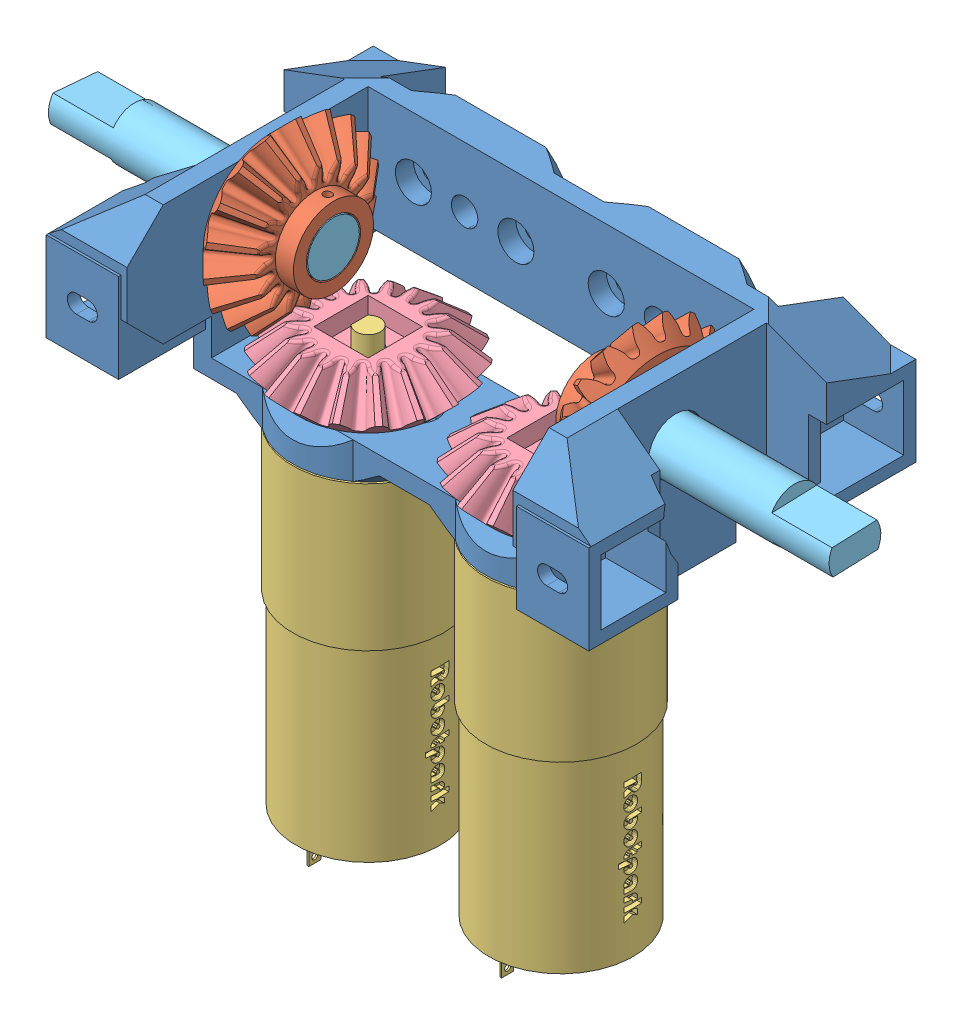
SolidWorks assembly Gearbox, configuration Default. Lengths in mm.
Overall size (157.67 110.2 59.04).
11 component instances, 5 part files, 21 mates.
Components (placement in the parent):
- Gearholder fine-1: Gearholder fine [Default] at (21.198 24.8446 19.4226) size (90 38 54.25)
- Bevel_Gear_18M3-2: Bevel_Gear_18M3 [Bevel01] at (39.7086 24.8446 38.4226) x (0 0.996387 -0.084925) z (1 0 0) size (54 54 28.01)
- Bevel_Gear_18M3-4: Bevel_Gear_18M3 [Bevel01] at (47.6874 24.8446 38.4226) x (0 -0.999352 -0.036007) z (-1 0 0) size (54 54 28.01)
- 25mm motor-1: 25mm motor [Default] at (47.7521 50.945 40.6836) x (0 -1 0) z (1 0 0) size (72.75 25 25)
  - A$C0AAA4746-1: A$C0AAA4746 [Default] at (70.7254 2.2611 11.9459) size (72.75 25 25)
- 25mm motor-2: 25mm motor [Default] at (15.7521 50.945 40.6836) x (0 -1 0) z (1 0 0) size (72.75 25 25)
  - A$C0AAA4746-1: A$C0AAA4746 [Default] at (70.7254 2.2611 11.9459) size (72.75 25 25)
- Bevel Gear Motor-1: Bevel Gear Motor [Bevel01] at (27.698 37.1053 38.4226) x (-1 0 0) z (0 1 0) size (54 54 28.01)
- Bevel Gear Motor-2: Bevel Gear Motor [Bevel01] at (59.698 37.1053 38.4226) x (-1 0 0) z (0 1 0) size (54 54 28.01)
- shaft - V2-1: shaft - V2 [Default] at (21.944 24.8446 38.4226) x (0 0.084925 0.996387) z (0 -0.996387 0.084925) size (9 57.08 9)
- shaft - V2-2: shaft - V2 [Default] at (65.452 24.8446 38.4226) x (0 0.036007 -0.999352) z (0 -0.999352 -0.036007) size (9 57.08 9)
Mates (geometry in assembly coordinates):
- Coincident2: coincident anti-aligned: plane of Gearholder fine-1 through (11.698 34.8446 62.4226) normal (1 0 0); plane of Bevel_Gear_18M3-2 through (11.698 24.8446 38.4226) normal (-1 0 0)
- Concentric2: concentric aligned: cylinder of Gearholder fine-1 through (78.698 24.8446 38.4226) axis (-1 0 0) radius 4.55; cylinder of Bevel_Gear_18M3-2 through (18.995 24.8446 38.4226) axis (-1 0 0) radius 4.5
- Concentric4: concentric anti-aligned: cylinder of Gearholder fine-1 through (78.698 24.8446 38.4226) axis (-1 0 0) radius 4.55; cylinder of Bevel_Gear_18M3-4 through (68.401 24.8446 38.4226) axis (1 0 0) radius 4.5
- Coincident4: coincident anti-aligned: plane of Gearholder fine-1 through (75.698 34.8446 82.6463) normal (-1 0 0); plane of Bevel_Gear_18M3-4 through (75.698 24.8446 38.4226) normal (1 0 0)
- Concentric11: concentric anti-aligned: cylinder of Bevel_Gear_18M3-2 through (18.995 24.8446 38.4226) axis (-1 0 0) radius 4.5; cylinder of ? through (-23.97 24.8446 38.4226) axis (1 0 0) radius 4.3
- Parallel3: parallel anti-aligned: line of Bevel_Gear_18M3-2 through (18.944 30.4777 41.3837) axis (0 -0.954912 0.296888); line of ? through (19.03 22.0151 43.8053) axis (0 0.954912 -0.296888)
- Concentric12: concentric anti-aligned: cylinder of Bevel_Gear_18M3-4 through (68.401 24.8446 38.4226) axis (1 0 0) radius 4.5; cylinder of ? through (111.452 24.8446 38.4226) axis (-1 0 0) radius 4.3
- Concentric19: concentric anti-aligned: cylinder of Gearholder fine-1 through (78.698 24.8446 38.4226) axis (-1 0 0) radius 4.55; cylinder of shaft - V2-1 through (-35.136 24.8446 38.4226) axis (1 0 0) radius 4.3
- Concentric20: concentric anti-aligned: cylinder of Gearholder fine-1 through (27.698 6.2446 38.4226) axis (0 -1 0) radius 3.7; cylinder of 25mm motor-2/A$C0AAA4746-1 through (27.698 3.3446 38.4226) axis (0 1 0) radius 3.5
- Concentric21: concentric anti-aligned: cylinder of Gearholder fine-1 through (36.198 5.8446 38.4226) axis (0 1 0) radius 1.5; cylinder of 25mm motor-2/A$C0AAA4746-1 through (36.198 0.0946 38.4226) axis (0 -1 0) radius 1.5
- Distance1: distance = 0.25 mm anti-aligned: plane of 25mm motor-2/A$C0AAA4746-1 through (27.698 2.5946 38.4226) normal (0 1 0); plane of Gearholder fine-1 through (27.698 2.8446 38.4226) normal (0 -1 0)
- Concentric22: concentric anti-aligned: cylinder of Gearholder fine-1 through (59.698 6.2446 38.4226) axis (0 -1 0) radius 3.7; cylinder of 25mm motor-1/A$C0AAA4746-1 through (59.698 3.3446 38.4226) axis (0 1 0) radius 3.5
- Concentric23: concentric anti-aligned: cylinder of Gearholder fine-1 through (68.198 5.8446 38.4226) axis (0 1 0) radius 1.5; cylinder of 25mm motor-1/A$C0AAA4746-1 through (68.198 0.0946 38.4226) axis (0 -1 0) radius 1.5
- Distance2: distance = 0.25 mm anti-aligned: plane of Gearholder fine-1 through (59.698 2.8446 38.4226) normal (0 -1 0); plane of 25mm motor-1/A$C0AAA4746-1 through (59.698 2.5946 38.4226) normal (0 1 0)
- Concentric24: concentric anti-aligned: cylinder of 25mm motor-1/A$C0AAA4746-1 through (59.698 10.3446 38.4226) axis (0 1 0) radius 2; cylinder of Bevel Gear Motor-2 through (59.698 16.3916 38.4226) axis (0 -1 0) radius 2.1
- Concentric28: concentric anti-aligned: cylinder of 25mm motor-2/A$C0AAA4746-1 through (27.698 10.3446 38.4226) axis (0 1 0) radius 2; cylinder of Bevel Gear Motor-1 through (27.698 16.3916 38.4226) axis (0 -1 0) radius 2.1
- Distance3: distance = 0.25 mm anti-aligned: plane of Bevel Gear Motor-1 through (27.698 9.0946 38.4226) normal (0 -1 0); plane of Gearholder fine-1 through (21.198 8.8446 19.4226) normal (0 1 0)
- Distance4: distance = 0.25 mm anti-aligned: plane of Bevel Gear Motor-2 through (59.698 9.0946 38.4226) normal (0 -1 0); plane of Gearholder fine-1 through (21.198 8.8446 19.4226) normal (0 1 0)
- Concentric29: concentric anti-aligned: cylinder of Bevel_Gear_18M3-2 through (20.444 10.0971 39.6795) axis (0 0.996387 -0.084925) radius 0.7; cylinder of shaft - V2-1 through (20.444 29.1291 38.0574) axis (0 -0.996387 0.084925) radius 0.6
- Concentric30: concentric anti-aligned: cylinder of Bevel_Gear_18M3-4 through (68.401 24.8446 38.4226) axis (1 0 0) radius 4.5; cylinder of shaft - V2-2 through (122.532 24.8446 38.4226) axis (-1 0 0) radius 4.3
- Concentric31: concentric aligned: cylinder of Bevel_Gear_18M3-4 through (66.952 39.636 38.9555) axis (0 -0.999352 -0.036007) radius 0.7; cylinder of shaft - V2-2 through (66.952 29.1418 38.5774) axis (0 -0.999352 -0.036007) radius 0.6
